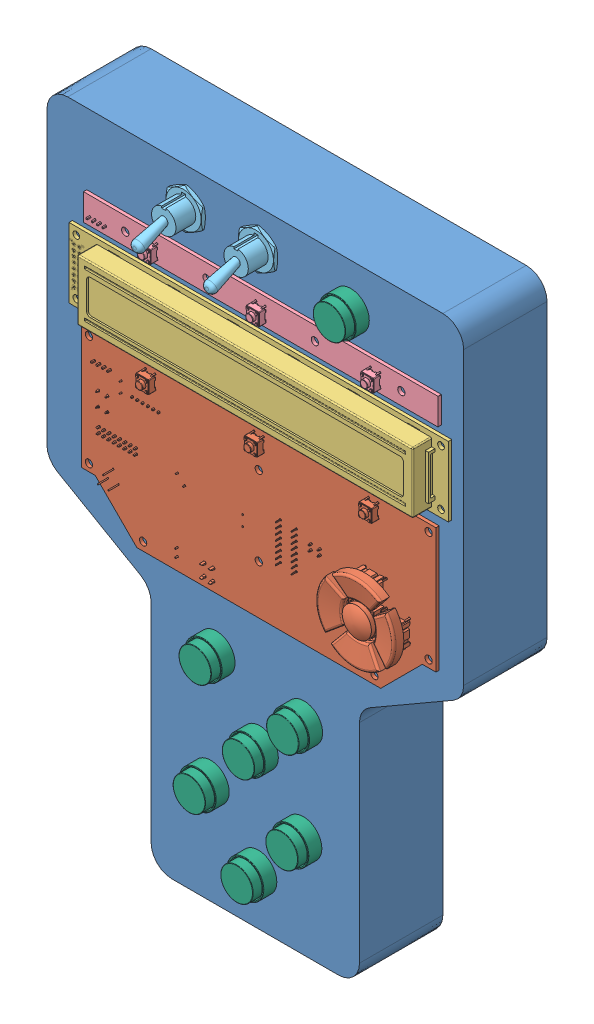
SolidWorks assembly Montagem 001, configuration Valor predeterminado. Lengths in mm.
Overall size (200 300 65.5).
13 component instances, 6 part files, 12 mates.
Components (placement in the parent):
- TEC01 - Base teclado -1: TEC01 - Base teclado  [Valor predeterminado] at (-37.031 -152.0804 300) size (200 300 40)
- PCB_IHM-1: PCB_IHM [Valor predeterminado] at (-118.7797 -1.203 321.5914) size (170 80 27.35)
- LCD Display 4002-1: LCD Display 4002 [Valor predeterminado] at (-33.8187 80.9175 317.0536) size (182 33.5 13.65)
- Teclado_Superior-1: Teclado_Superior [Valor predeterminado] at (-117.8583 40.2839 321.5914) size (170.25 12.75 19.2)
- BCV3 112 103 - Controle chave geral-1: BCV3 112 103 - Controle chave geral [Default] at (-69.4632 130.8608 310.5) size (17 29 51.5)
- BCV3 112 103 - Controle chave geral-2: BCV3 112 103 - Controle chave geral [Default] at (-34.7511 131.3218 310.5) size (17 29 51.5)
- BCV3 112 102 - Controle botão-1: BCV3 112 102 - Controle botão [Valor predeterminado] at (-13.9693 -103.504 320) x (1 0 0) z (0 -1 0) size (17.7 39.7 17.7)
- BCV3 112 102 - Controle botão-2: BCV3 112 102 - Controle botão [Valor predeterminado] at (-55.6109 -47.2108 320) x (1 0 0) z (0 -1 0) size (17.7 39.7 17.7)
- BCV3 112 102 - Controle botão-3: BCV3 112 102 - Controle botão [Valor predeterminado] at (-35.5713 -128.2117 320) x (1 0 0) z (0 -1 0) size (17.7 39.7 17.7)
- BCV3 112 102 - Controle botão-4: BCV3 112 102 - Controle botão [Valor predeterminado] at (-34.8532 -76.1724 320) x (1 0 0) z (0 -1 0) size (17.7 39.7 17.7)
- BCV3 112 102 - Controle botão-5: BCV3 112 102 - Controle botão [Valor predeterminado] at (-58.4381 -102.2945 320) x (1 0 0) z (0 -1 0) size (17.7 39.7 17.7)
- BCV3 112 102 - Controle botão-6: BCV3 112 102 - Controle botão [Valor predeterminado] at (8.7982 127.3498 320) x (1 0 0) z (0 -1 0) size (17.7 39.7 17.7)
- BCV3 112 102 - Controle botão-9: BCV3 112 102 - Controle botão [Valor predeterminado] at (-13.5954 -55.2607 320) x (1 0 0) z (0 -1 0) size (17.7 39.7 17.7)
Mates (geometry in assembly coordinates):
- Coincidente1: coincident anti-aligned: plane of TEC01 - Base teclado -1 through (-127.031 137.9196 320) normal (0 0 1); plane of PCB_IHM-1 through (-118.7797 -1.203 320) normal (0 0 -1)
- Coincidente2: coincident anti-aligned: plane of TEC01 - Base teclado -1 through (-127.031 137.9196 320) normal (0 0 1); plane of LCD Display 4002-1 through (-33.8187 80.9175 320) normal (0 0 -1)
- Coincidente3: coincident anti-aligned: plane of TEC01 - Base teclado -1 through (-127.031 137.9196 320) normal (0 0 1); plane of Teclado_Superior-1 through (-117.8583 101.1569 320) normal (0 0 -1)
- Coincidente4: coincident anti-aligned: plane of TEC01 - Base teclado -1 through (-127.031 137.9196 320) normal (0 0 1); plane of BCV3 112 103 - Controle chave geral-2 through (-34.7511 141.1368 320) normal (0 0 -1)
- Coincidente5: coincident anti-aligned: plane of TEC01 - Base teclado -1 through (-127.031 137.9196 320) normal (0 0 1); plane of BCV3 112 103 - Controle chave geral-1 through (-69.4632 140.6758 320) normal (0 0 -1)
- Coincidente6: coincident anti-aligned: plane of TEC01 - Base teclado -1 through (-127.031 137.9196 320) normal (0 0 1); plane of BCV3 112 102 - Controle botão-1 through (-13.9693 -103.504 320) normal (0 0 -1)
- Coincidente7: coincident anti-aligned: plane of TEC01 - Base teclado -1 through (-127.031 137.9196 320) normal (0 0 1); plane of BCV3 112 102 - Controle botão-4 through (-34.8532 -76.1724 320) normal (0 0 -1)
- Coincidente8: coincident anti-aligned: plane of TEC01 - Base teclado -1 through (-127.031 137.9196 320) normal (0 0 1); plane of BCV3 112 102 - Controle botão-5 through (-58.4381 -102.2945 320) normal (0 0 -1)
- Coincidente9: coincident anti-aligned: plane of TEC01 - Base teclado -1 through (-127.031 137.9196 320) normal (0 0 1); plane of BCV3 112 102 - Controle botão-3 through (-35.5713 -128.2117 320) normal (0 0 -1)
- Coincidente10: coincident anti-aligned: plane of TEC01 - Base teclado -1 through (-127.031 137.9196 320) normal (0 0 1); plane of BCV3 112 102 - Controle botão-2 through (-55.6109 -47.2108 320) normal (0 0 -1)
- Coincidente11: coincident anti-aligned: plane of TEC01 - Base teclado -1 through (-127.031 137.9196 320) normal (0 0 1); plane of BCV3 112 102 - Controle botão-6 through (8.7982 127.3498 320) normal (0 0 -1)
- Coincidente15: coincident anti-aligned: plane of TEC01 - Base teclado -1 through (-127.031 137.9196 320) normal (0 0 1); plane of BCV3 112 102 - Controle botão-9 through (-13.5954 -55.2607 320) normal (0 0 -1)
